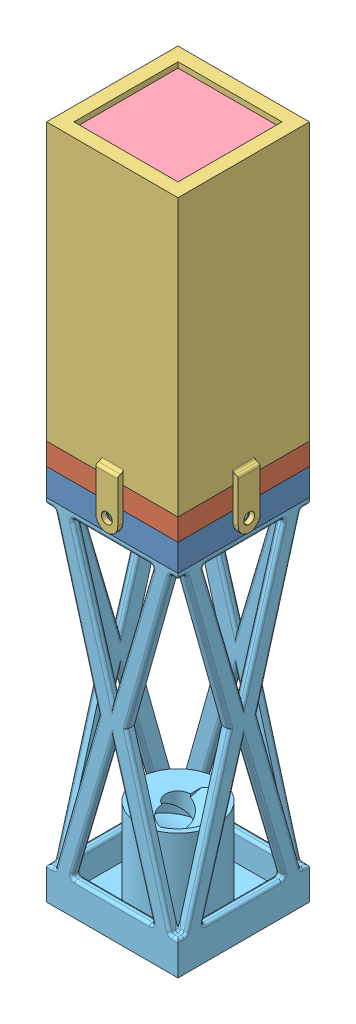
SolidWorks assembly Pin_Assembly, configuration Default. Lengths in mm.
Overall size (41.27 200.82 41.28).
5 component instances, 5 part files, 11 mates.
Components (placement in the parent):
- Lower_Pin_Upper-1: Lower_Pin_Upper [Default] at (33.479 -32.182 75.6775) size (38.1 7.81 38.1)
- Board_Plate-1: Board_Plate [Default] at (33.479 69.291 75.6775) x (-1 0 0) z (0 0 -1) size (38.1 6.86 38.1)
- Upper_Pin-1: Upper_Pin [Default] at (33.479 70.8785 75.6775) size (41.27 92.87 41.27)
- Pin_Surface-1: Pin_Surface [Default] at (33.5584 76.5173 75.7569) size (34.54 72.15 34.54)
- Lower_Pin_Lower_V3-1: Lower_Pin_Lower_V3 [Default] at (33.479 -44.882 75.6775) size (38.1 107.68 38.1)
Mates (geometry in assembly coordinates):
- Coincident4: coincident aligned: plane of Lower_Pin_Upper-1 through (33.479 56.718 56.6275) normal (0 0 -1); plane of Board_Plate-1 through (52.529 64.5285 56.6275) normal (0 0 -1)
- Coincident5: coincident aligned: plane of Lower_Pin_Upper-1 through (52.529 56.718 75.6775) normal (1 0 0); plane of Board_Plate-1 through (52.529 64.5285 94.7275) normal (1 0 0)
- Coincident6: coincident anti-aligned: plane of Lower_Pin_Upper-1 through (33.479 64.5285 75.6775) normal (0 1 0); plane of Board_Plate-1 through (33.479 64.5285 75.6775) normal (0 -1 0)
- Concentric1: concentric anti-aligned: circle of Lower_Pin_Upper-1; cylinder of Upper_Pin-1 through (33.479 61.8615 45.515) axis (0 0 1) radius 1.5875
- Concentric2: concentric aligned: circle of Lower_Pin_Upper-1; circle of Upper_Pin-1
- Distance1: distance = 0.3969 mm anti-aligned: plane of Upper_Pin-1 through (16.0165 149.4598 58.215) normal (1 0 0); plane of Pin_Surface-1 through (16.4134 148.666 92.9019) normal (-1 0 0)
- Distance2: distance = 0.3969 mm anti-aligned: plane of Pin_Surface-1 through (16.4134 148.666 58.6119) normal (0 0 -1); plane of Upper_Pin-1 through (16.0165 149.4598 58.215) normal (0 0 1)
- Distance3: distance = 2.3813 mm aligned: plane of Pin_Surface-1 through (33.5584 148.666 75.7569) normal (0 1 0); plane of Upper_Pin-1 through (33.479 151.0473 75.6775) normal (0 1 0)
- Coincident7: coincident aligned: plane of Lower_Pin_Upper-1 through (52.529 56.718 75.6775) normal (1 0 0); plane of Lower_Pin_Lower_V3-1 through (52.529 56.718 75.6775) normal (1 0 0)
- Coincident8: coincident aligned: plane of Lower_Pin_Upper-1 through (33.479 56.718 94.7275) normal (0 0 1); plane of Lower_Pin_Lower_V3-1 through (33.479 56.718 94.7275) normal (0 0 1)
- Coincident9: coincident anti-aligned: plane of Lower_Pin_Upper-1 through (33.479 56.718 75.6775) normal (0 -1 0); plane of Lower_Pin_Lower_V3-1 through (33.479 56.718 75.6775) normal (0 1 0)
